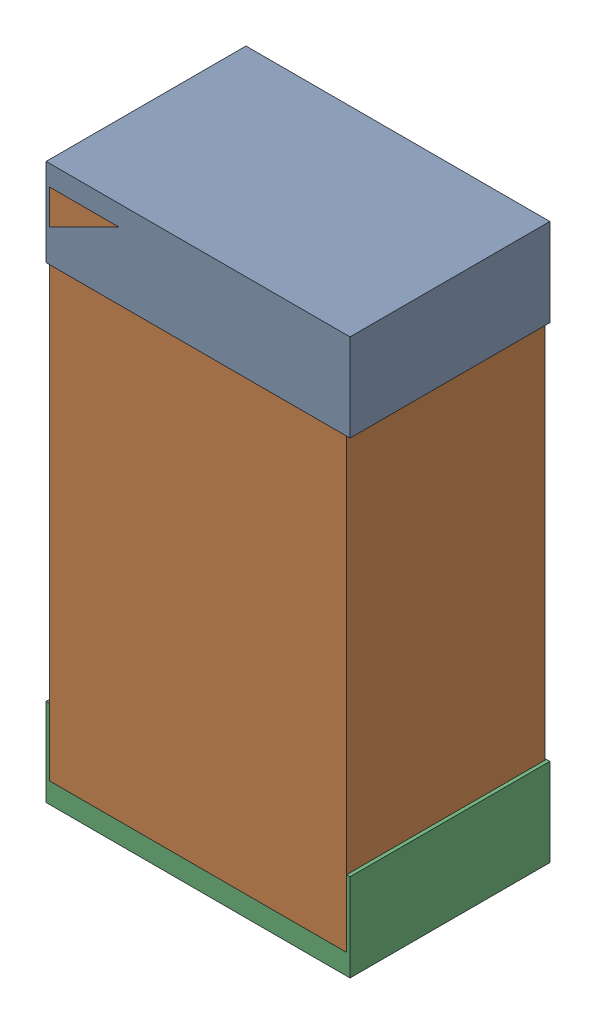
SolidWorks assembly R10Kanaloa_v2.0.0_Power, configuration Default. Lengths in mm.
Overall size (1.3 2.38 0.85).
6 component instances, 2 part files, 0 mates.
Components (placement in the parent):
- 330415056-1: 330415056 [Default] at (90.7796 41.132 -1.9574) size (1.3 0.38 0.85)
  - Extruded_2-1: Extruded_2 [Default] at origin size (1.3 0.38 0.85)
- 352877008-1: 352877008 [Default] at (90.7796 40.132 -1.9524) size (1.27 2.2 0.85)
  - Extruded_3-1: Extruded_3 [Default] at origin size (1.27 2.2 0.85)
- 330415056-2: 330415056 [Default] at (90.7796 39.132 -1.9574) size (1.3 0.38 0.85)
  - Extruded_2-1: Extruded_2 [Default] at origin size (1.3 0.38 0.85)
